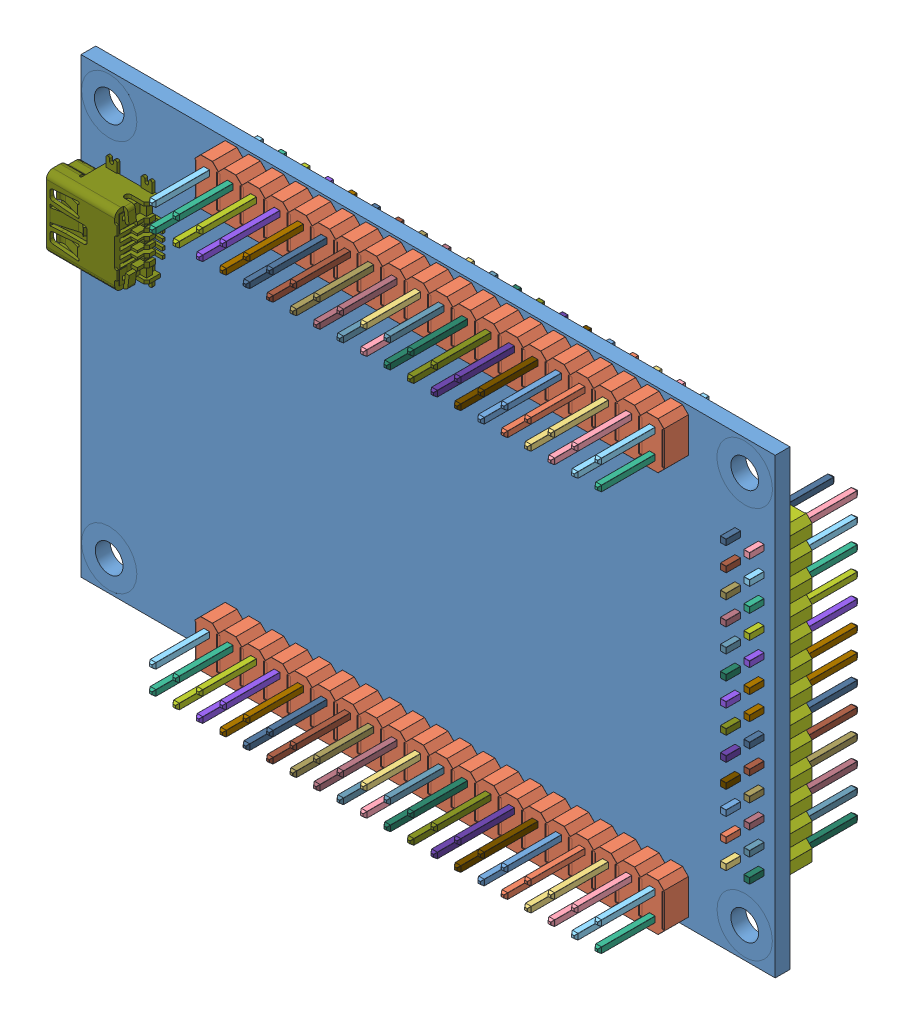
SolidWorks assembly DE0 Nano v14, configuration Exploded View. Lengths in mm.
Overall size (75.18 49.02 19.03).
118 component instances, 70 part files, 0 mates.
Components (placement in the parent):
- DE0 Circuit Board-1: DE0 Circuit Board [Default] at origin size (75.18 49.02 1.6)
- Connectors-1: Connectors [Default] at origin size (74.72 48.4 19.03)
  - 2x20 Male 0.1in Header Connector-1: 2x20 Male 0.1in Header Connector [Default] at (1.53 -21.59 1.6002) size (50.8 5.09 11.89)
    - Plastic-1: Plastic [Default] at origin size (50.8 5.09 2.67)
    - Pins-1: Pins [Default] at origin size (48.9 3.18 11.89)
      - Pins_34-1: Pins_34 [Default] at origin size (0.64 0.64 11.89)
      - Pins_30-1: Pins_30 [Default] at origin size (0.64 0.64 11.89)
      - Pins_33-1: Pins_33 [Default] at origin size (0.64 0.64 11.89)
      - Pins_24-1: Pins_24 [Default] at origin size (0.64 0.64 11.89)
      - Pins_10-1: Pins_10 [Default] at origin size (0.64 0.64 11.89)
      - Pins_39-1: Pins_39 [Default] at origin size (0.64 0.64 11.89)
      - Pins_6-1: Pins_6 [Default] at origin size (0.64 0.64 11.89)
      - Pins_2-1: Pins_2 [Default] at origin size (0.64 0.64 11.89)
      - Pins_28-1: Pins_28 [Default] at origin size (0.64 0.64 11.89)
      - Pins_25-1: Pins_25 [Default] at origin size (0.64 0.64 11.89)
      - Pins_12-1: Pins_12 [Default] at origin size (0.64 0.64 11.89)
      - Pins_16-1: Pins_16 [Default] at origin size (0.64 0.64 11.89)
      - Pins-1: Pins [Default] at origin size (0.64 0.64 11.89)
      - Pins_40-1: Pins_40 [Default] at origin size (0.64 0.64 11.89)
      - Pins_18-1: Pins_18 [Default] at origin size (0.64 0.64 11.89)
      - Pins_32-1: Pins_32 [Default] at origin size (0.64 0.64 11.89)
      - Pins_15-1: Pins_15 [Default] at origin size (0.64 0.64 11.89)
      - Pins_35-1: Pins_35 [Default] at origin size (0.64 0.64 11.89)
      - Pins_7-1: Pins_7 [Default] at origin size (0.64 0.64 11.89)
      - Pins_20-1: Pins_20 [Default] at origin size (0.64 0.64 11.89)
      - Pins_27-1: Pins_27 [Default] at origin size (0.64 0.64 11.89)
      - Pins_29-1: Pins_29 [Default] at origin size (0.64 0.64 11.89)
      - Pins_19-1: Pins_19 [Default] at origin size (0.64 0.64 11.89)
      - Pins_37-1: Pins_37 [Default] at origin size (0.64 0.64 11.89)
      - Pins_38-1: Pins_38 [Default] at origin size (0.64 0.64 11.89)
      - Pins_23-1: Pins_23 [Default] at origin size (0.64 0.64 11.89)
      - Pins_4-1: Pins_4 [Default] at origin size (0.64 0.64 11.89)
      - Pins_36-1: Pins_36 [Default] at origin size (0.64 0.64 11.89)
      - Pins_26-1: Pins_26 [Default] at origin size (0.64 0.64 11.89)
      - Pins_8-1: Pins_8 [Default] at origin size (0.64 0.64 11.89)
      - Pins_9-1: Pins_9 [Default] at origin size (0.64 0.64 11.89)
      - Pins_13-1: Pins_13 [Default] at origin size (0.64 0.64 11.89)
      - Pins_3-1: Pins_3 [Default] at origin size (0.64 0.64 11.89)
      - Pins_5-1: Pins_5 [Default] at origin size (0.64 0.64 11.89)
      - Pins_31-1: Pins_31 [Default] at origin size (0.64 0.64 11.89)
      - Pins_21-1: Pins_21 [Default] at origin size (0.64 0.64 11.89)
      - Pins_11-1: Pins_11 [Default] at origin size (0.64 0.64 11.89)
      - Pins_14-1: Pins_14 [Default] at origin size (0.64 0.64 11.89)
      - Pins_17-1: Pins_17 [Default] at origin size (0.64 0.64 11.89)
      - Pins_22-1: Pins_22 [Default] at origin size (0.64 0.64 11.89)
  - 2x20 Male 0.1in Header Connector_1-1: 2x20 Male 0.1in Header Connector_1 [Default] at (1.53 21.72 1.6002) size (50.8 5.09 11.89)
    - Plastic-1: Plastic [Default] at origin size (50.8 5.09 2.67)
    - Pins-1: Pins [Default] at origin size (48.9 3.18 11.89)
      - Pins_34-1: Pins_34 [Default] at origin size (0.64 0.64 11.89)
      - Pins_30-1: Pins_30 [Default] at origin size (0.64 0.64 11.89)
      - Pins_33-1: Pins_33 [Default] at origin size (0.64 0.64 11.89)
      - Pins_24-1: Pins_24 [Default] at origin size (0.64 0.64 11.89)
      - Pins_10-1: Pins_10 [Default] at origin size (0.64 0.64 11.89)
      - Pins_39-1: Pins_39 [Default] at origin size (0.64 0.64 11.89)
      - Pins_6-1: Pins_6 [Default] at origin size (0.64 0.64 11.89)
      - Pins_2-1: Pins_2 [Default] at origin size (0.64 0.64 11.89)
      - Pins_28-1: Pins_28 [Default] at origin size (0.64 0.64 11.89)
      - Pins_25-1: Pins_25 [Default] at origin size (0.64 0.64 11.89)
      - Pins_12-1: Pins_12 [Default] at origin size (0.64 0.64 11.89)
      - Pins_16-1: Pins_16 [Default] at origin size (0.64 0.64 11.89)
      - Pins-1: Pins [Default] at origin size (0.64 0.64 11.89)
      - Pins_40-1: Pins_40 [Default] at origin size (0.64 0.64 11.89)
      - Pins_18-1: Pins_18 [Default] at origin size (0.64 0.64 11.89)
      - Pins_32-1: Pins_32 [Default] at origin size (0.64 0.64 11.89)
      - Pins_15-1: Pins_15 [Default] at origin size (0.64 0.64 11.89)
      - Pins_35-1: Pins_35 [Default] at origin size (0.64 0.64 11.89)
      - Pins_7-1: Pins_7 [Default] at origin size (0.64 0.64 11.89)
      - Pins_20-1: Pins_20 [Default] at origin size (0.64 0.64 11.89)
      - Pins_27-1: Pins_27 [Default] at origin size (0.64 0.64 11.89)
      - Pins_29-1: Pins_29 [Default] at origin size (0.64 0.64 11.89)
      - Pins_19-1: Pins_19 [Default] at origin size (0.64 0.64 11.89)
      - Pins_37-1: Pins_37 [Default] at origin size (0.64 0.64 11.89)
      - Pins_38-1: Pins_38 [Default] at origin size (0.64 0.64 11.89)
      - Pins_23-1: Pins_23 [Default] at origin size (0.64 0.64 11.89)
      - Pins_4-1: Pins_4 [Default] at origin size (0.64 0.64 11.89)
      - Pins_36-1: Pins_36 [Default] at origin size (0.64 0.64 11.89)
      - Pins_26-1: Pins_26 [Default] at origin size (0.64 0.64 11.89)
      - Pins_8-1: Pins_8 [Default] at origin size (0.64 0.64 11.89)
      - Pins_9-1: Pins_9 [Default] at origin size (0.64 0.64 11.89)
      - Pins_13-1: Pins_13 [Default] at origin size (0.64 0.64 11.89)
      - Pins_3-1: Pins_3 [Default] at origin size (0.64 0.64 11.89)
      - Pins_5-1: Pins_5 [Default] at origin size (0.64 0.64 11.89)
      - Pins_31-1: Pins_31 [Default] at origin size (0.64 0.64 11.89)
      - Pins_21-1: Pins_21 [Default] at origin size (0.64 0.64 11.89)
      - Pins_11-1: Pins_11 [Default] at origin size (0.64 0.64 11.89)
      - Pins_14-1: Pins_14 [Default] at origin size (0.64 0.64 11.89)
      - Pins_17-1: Pins_17 [Default] at origin size (0.64 0.64 11.89)
      - Pins_22-1: Pins_22 [Default] at origin size (0.64 0.64 11.89)
  - 2x13 Male 0.1in Header Connector-1: 2x13 Male 0.1in Header Connector [Default] at (34.8 0 0.0002) x (0 -1 0) z (0 0 -1) size (33.02 5.09 11.89)
    - Plastic_1-1: Plastic_1 [Default] at origin size (33.02 5.09 2.67)
    - Pins_1-1: Pins_1 [Default] at origin size (31.12 3.18 11.89)
      - Pins_1_16-1: Pins_1_16 [Default] at origin size (0.64 0.64 11.89)
      - Pins_1_2-1: Pins_1_2 [Default] at origin size (0.64 0.64 11.89)
      - Pins_1_24-1: Pins_1_24 [Default] at origin size (0.64 0.64 11.89)
      - Pins_1_19-1: Pins_1_19 [Default] at origin size (0.64 0.64 11.89)
      - Pins_1_12-1: Pins_1_12 [Default] at origin size (0.64 0.64 11.89)
      - Pins_1_7-1: Pins_1_7 [Default] at origin size (0.64 0.64 11.89)
      - Pins_1_5-1: Pins_1_5 [Default] at origin size (0.64 0.64 11.89)
      - Pins_1_13-1: Pins_1_13 [Default] at origin size (0.64 0.64 11.89)
      - Pins_1_8-1: Pins_1_8 [Default] at origin size (0.64 0.64 11.89)
      - Pins_1_3-1: Pins_1_3 [Default] at origin size (0.64 0.64 11.89)
      - Pins_1_22-1: Pins_1_22 [Default] at origin size (0.64 0.64 11.89)
      - Pins_1_18-1: Pins_1_18 [Default] at origin size (0.64 0.64 11.89)
      - Pins_1_20-1: Pins_1_20 [Default] at origin size (0.64 0.64 11.89)
      - Pins_1_23-1: Pins_1_23 [Default] at origin size (0.64 0.64 11.89)
      - Pins_1_25-1: Pins_1_25 [Default] at origin size (0.64 0.64 11.89)
      - Pins_1_26-1: Pins_1_26 [Default] at origin size (0.64 0.64 11.89)
      - Pins_1_10-1: Pins_1_10 [Default] at origin size (0.64 0.64 11.89)
      - Pins_1_15-1: Pins_1_15 [Default] at origin size (0.64 0.64 11.89)
      - Pins_1_14-1: Pins_1_14 [Default] at origin size (0.64 0.64 11.89)
      - Pins_1-1: Pins_1 [Default] at origin size (0.64 0.64 11.89)
      - Pins_1_4-1: Pins_1_4 [Default] at origin size (0.64 0.64 11.89)
      - Pins_1_21-1: Pins_1_21 [Default] at origin size (0.64 0.64 11.89)
      - Pins_1_6-1: Pins_1_6 [Default] at origin size (0.64 0.64 11.89)
      - Pins_1_11-1: Pins_1_11 [Default] at origin size (0.64 0.64 11.89)
      - Pins_1_9-1: Pins_1_9 [Default] at origin size (0.64 0.64 11.89)
      - Pins_1_17-1: Pins_1_17 [Default] at origin size (0.64 0.64 11.89)
  - USB_Mini_B_SMD_buchse-1: USB_Mini_B_SMD_buchse [Default] at (-37.9777 11.749 3.6149) x (0 -1 0) z (-1 0 0) size (10 3.97 8.9)
